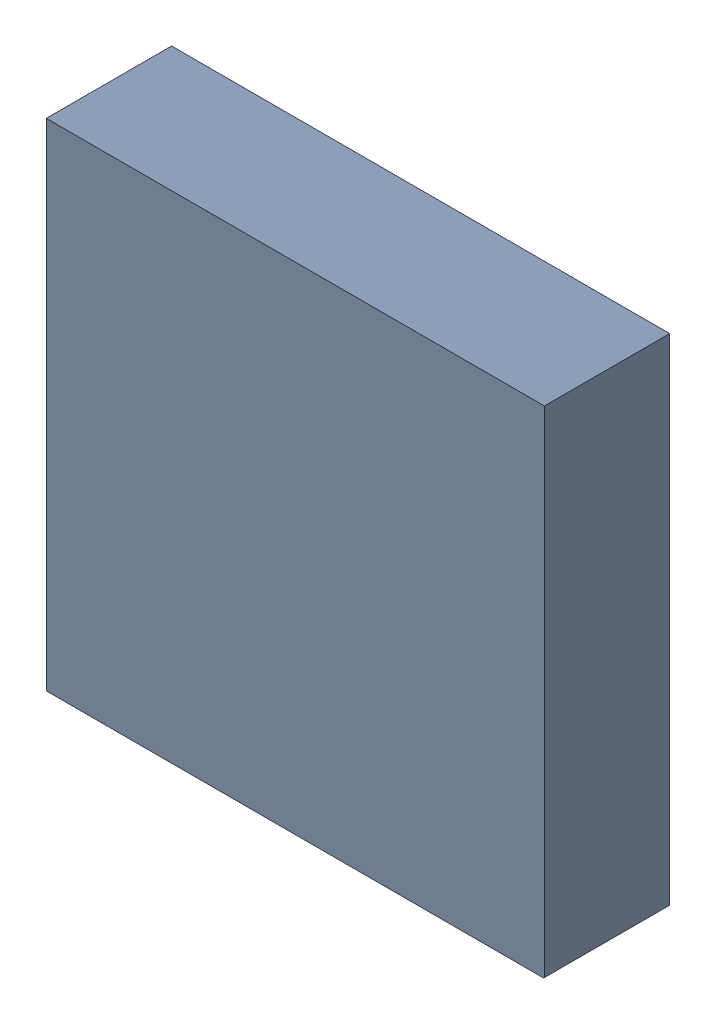
SolidWorks assembly U1, configuration 默认. Lengths in mm.
Overall size (3.19 3.17 0.82).
4 component instances, 2 part files, 0 mates.
Components (placement in the parent):
- 6641441568-1: 6641441568 [默认] at (6.25 17.0875 -2.7339) size (3.19 3.17 0.81)
  - Extruded-21-1: Extruded-21 [默认] at origin size (3.19 3.17 0.81)
- 6641441328-1: 6641441328 [默认] at (7.5108 18.3998 -2.7339) x (-1 0 0) z (0 0 -1) size (0.2 0.2 0.01)
  - Cylinder-22-1: Cylinder-22 [默认] at origin size (0.2 0.2 0.01)
